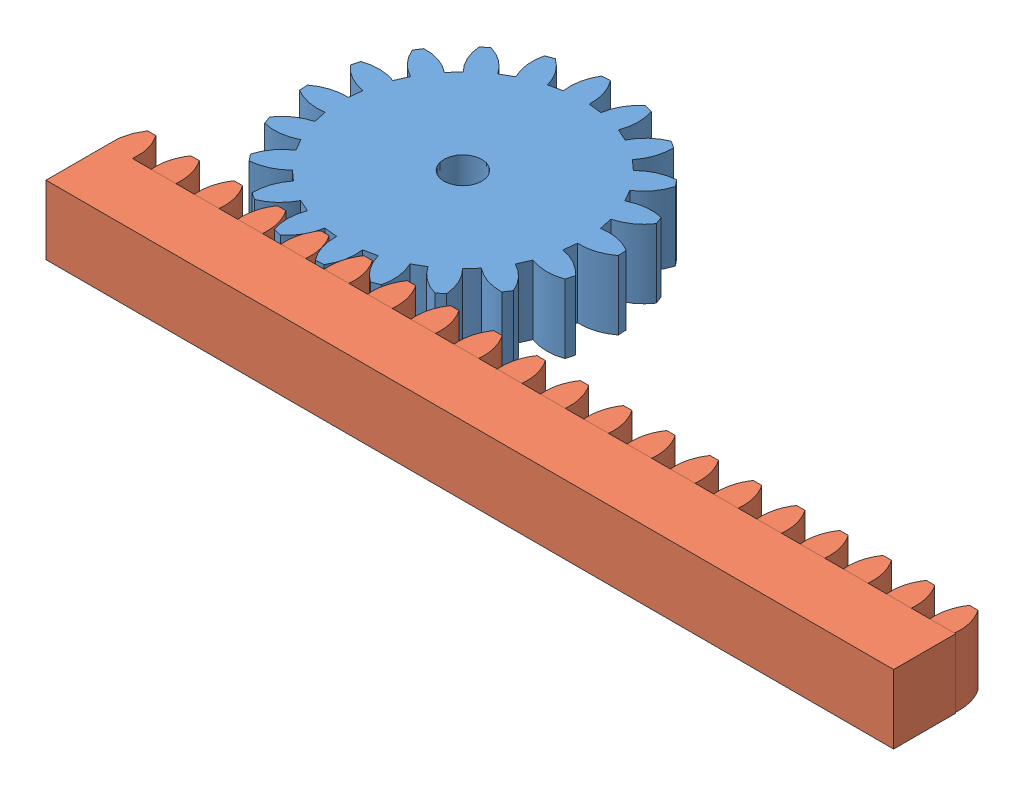
SolidWorks assembly 齿轮齿条, configuration 默认. Lengths in mm.
Overall size (125.09 10 62.56).
2 component instances, 2 part files, 6 mates.
Components (placement in the parent):
- 齿轮-1: 齿轮 [默认] at (0 -10 0) x (0.689072 0 0.724693) z (-0.724693 0 0.689072) size (43.94 10 43.94)
- 齿条-1: 齿条 [默认] at (-29.0208 -10 22.5) size (123.09 10 13.58)
Mates (geometry in assembly coordinates):
- 同心1: concentric: cylinder of 齿轮-1 through (0 -10 0) axis (0 1 0) radius 2.7524
- 重合1: coincident aligned: plane of 齿轮-1 through (0 0 0) normal (0 1 0)
- 距离2: distance = 22.5 mm: plane of 齿条-1 through (-29.0208 -10 22.5) normal (0 0 -1); cylinder of 齿轮-1 through (0 -10 0) axis (0 1 0) radius 2.7524
- 重合2: coincident aligned: plane of 齿轮-1 through (0 0 0) normal (0 1 0); plane of 齿条-1 through (-22.2161 0 21.802) normal (0 1 0)
- RackPinionMate1: rack pinion = 20 mm: cylinder of 齿条-1 through (-0.8571 0 21.802) axis (0 -1 0) radius 6.8404; cylinder of 齿轮-1 through (11.194 0 15.0965) axis (0 -1 0) radius 6.8404
- 平行1: parallel aligned: plane of 齿条-1 through (-29.0208 -10 31.5) normal (0 0 1)
